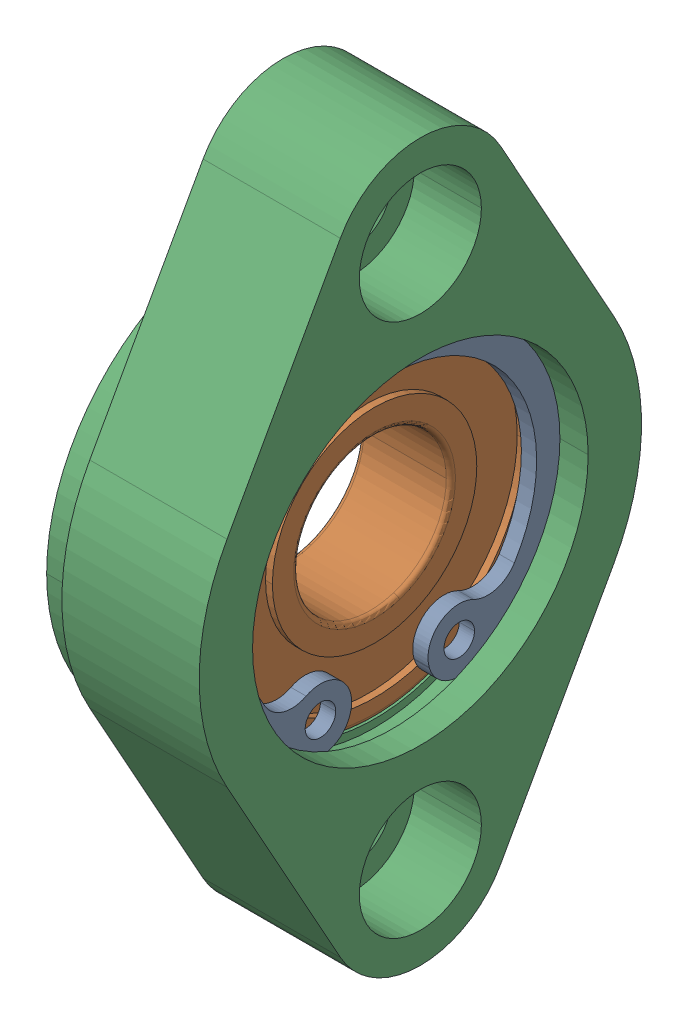
SolidWorks assembly V8_bearingC_BACR6900ZZURC 2024, configuration Default. Lengths in mm.
Overall size (11 47 29).
3 component instances, 3 part files, 0 mates.
Components (placement in the parent):
- V8_bearingC_BACR6900ZZ_3URC 2024-1: V8_bearingC_BACR6900ZZ_3URC 2024 [Default] at (-2.5 0 0) size (1 21.86 23)
- V8_bearingC_BACR6900ZZ_5URC 2024-1: V8_bearingC_BACR6900ZZ_5URC 2024 [Default] at (-9 0 0) size (6 22 22)
- V8_bearingC_BACR6900ZZ_7URC 2024-1: V8_bearingC_BACR6900ZZ_7URC 2024 [Default] at origin size (11 47 29)
